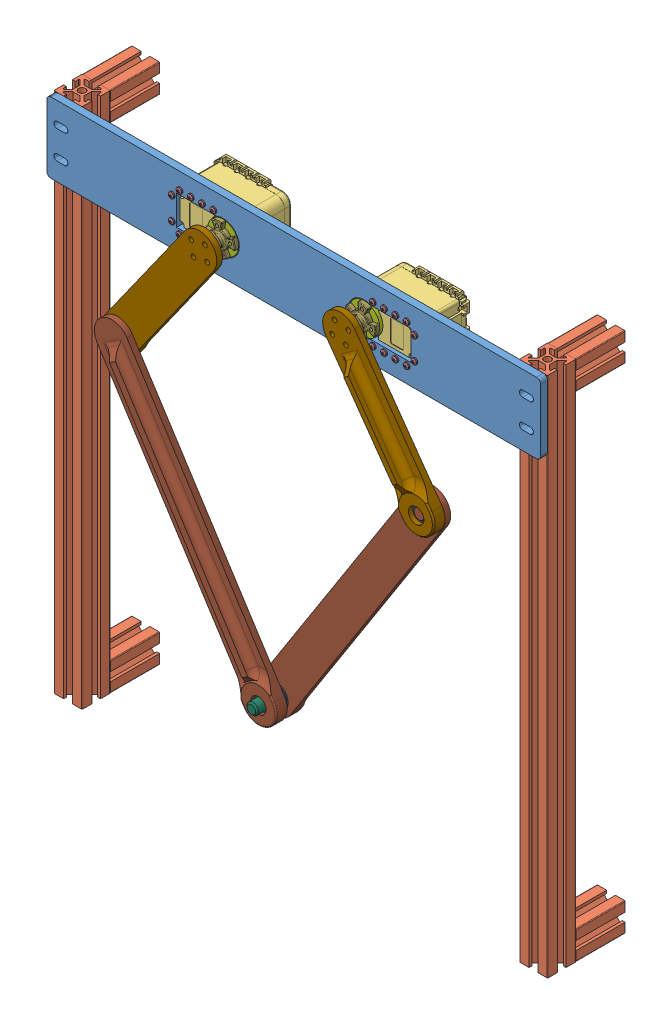
SolidWorks assembly Final Assembly, configuration Default. Lengths in mm.
Overall size (350 370 90).
75 component instances, 15 part files, 116 mates.
Components (placement in the parent):
- Motor Mount Plate-1: Motor Mount Plate [Default] at (0 0 -16) size (350 50 5)
- 2 Dof StrutralBase-1: 2 Dof StrutralBase [Default<As Machined>] at (0 -160 -31) x (1 0 0) z (0 -1 0) size (350 55 370)
- AX-12.stp-1: AX-12.stp [Default] at (-50 0 -37) x (0 -1 0) z (0 0 1) size (32 50 40.86)
  - ASSY_DUMMY__.stp-1: ASSY_DUMMY__.stp [Default] at origin size (32 50 38)
  - ASSY_GEAR-WHEEL__.stp-1: ASSY_GEAR-WHEEL__.stp [Default] at (0 0 -1.8) size (6.5 6.5 5.5)
  - DX124_SCREW-COVER__.stp-1: DX124_SCREW-COVER__.stp [Default] at (9 8.5 14.6) x (-1 0 0) z (0 1 0) size (3.5 30.65 3.5)
  - DX124_SCREW-COVER__.stp-2: DX124_SCREW-COVER__.stp [Default] at (-9 8.5 14.6) x (-1 0 0) z (0 1 0) size (3.5 30.65 3.5)
  - DX124_SCREW-COVER__.stp-3: DX124_SCREW-COVER__.stp [Default] at (9.15 -31.65 14.6) x (-1 0 0) z (0 1 0) size (3.5 30.65 3.5)
  - DX124_SCREW-COVER__.stp-4: DX124_SCREW-COVER__.stp [Default] at (-9 -31.65 14.6) x (-1 0 0) z (0 1 0) size (3.5 30.65 3.5)
  - 099990987___.stp-1: 099990987___.stp [Default] at (5.35 -15.67 -8.55) x (1 0 0) z (0 1 0) size (9.9 9.4 4.9)
  - 099990987___.stp-2: 099990987___.stp [Default] at (-5.3 -15.67 -8.55) x (1 0 0) z (0 1 0) size (9.9 9.4 4.9)
  - DX124_HORN1__.stp-1: DX124_HORN1__.stp [Default] at (0 0 19) x (0 1 0) z (0 0 1) size (22 22 7.6)
  - PHS_M3X10__.stp-1: PHS_M3X10__.stp [Default] at (0 0 19.9) x (-1 0 0) z (0 1 0) size (5.5 11.96 5.5)
- AX-12.stp-2: AX-12.stp [Default] at (50 0 -37) x (0 1 0) z (0 0 1) size (32 50 40.86)
  - ASSY_DUMMY__.stp-1: ASSY_DUMMY__.stp [Default] at origin size (32 50 38)
  - ASSY_GEAR-WHEEL__.stp-1: ASSY_GEAR-WHEEL__.stp [Default] at (0 0 -1.8) size (6.5 6.5 5.5)
  - DX124_SCREW-COVER__.stp-1: DX124_SCREW-COVER__.stp [Default] at (9 8.5 14.6) x (-1 0 0) z (0 1 0) size (3.5 30.65 3.5)
  - DX124_SCREW-COVER__.stp-2: DX124_SCREW-COVER__.stp [Default] at (-9 8.5 14.6) x (-1 0 0) z (0 1 0) size (3.5 30.65 3.5)
  - DX124_SCREW-COVER__.stp-3: DX124_SCREW-COVER__.stp [Default] at (9.15 -31.65 14.6) x (-1 0 0) z (0 1 0) size (3.5 30.65 3.5)
  - DX124_SCREW-COVER__.stp-4: DX124_SCREW-COVER__.stp [Default] at (-9 -31.65 14.6) x (-1 0 0) z (0 1 0) size (3.5 30.65 3.5)
  - 099990987___.stp-1: 099990987___.stp [Default] at (5.35 -15.67 -8.55) x (1 0 0) z (0 1 0) size (9.9 9.4 4.9)
  - 099990987___.stp-2: 099990987___.stp [Default] at (-5.3 -15.67 -8.55) x (1 0 0) z (0 1 0) size (9.9 9.4 4.9)
  - DX124_HORN1__.stp-1: DX124_HORN1__.stp [Default] at (0 0 19) x (0 1 0) z (0 0 1) size (22 22 7.6)
  - PHS_M3X10__.stp-1: PHS_M3X10__.stp [Default] at (0 0 19.9) x (-1 0 0) z (0 1 0) size (5.5 11.96 5.5)
- Top Link-5: Top Link [Default] at (0 0 -3) size (82.85 106.57 12)
- Top Link-6: Top Link [Default] at (0 0 1) x (-1 0 0) z (0 0 -1) size (82.85 106.57 12)
- Ball Bearing 8 x 16 x 5.step-1: Ball Bearing 8 x 16 x 5.step [Default] at (-107.8481 -81.5696 -1.5) x (0 0 -1) z (-0.985237 -0.171198 0) size (5 16 16)
- Ball Bearing 8 x 16 x 5.step-2: Ball Bearing 8 x 16 x 5.step [Default] at (107.8481 -81.5696 -0.5) x (0 0 -1) z (0.941995 -0.335626 0) size (5 16 16)
- Bottom Link-4: Bottom Link [Default] at (-107.8481 -81.5696 1) x (0.842152 0.53924 0) z (0 0 1) size (25 225 16.9)
- Bottom Link-5: Bottom Link [Default] at (107.8481 -81.5696 -3) x (-0.842152 0.53924 0) z (0 0 -1) size (25 225 16.9)
- Ball Bearing 8 x 16 x 5.step-3: Ball Bearing 8 x 16 x 5.step [Default] at (0 -250 -5.5) x (0 0 -1) z (-0.399255 -0.91684 0) size (5 16 16)
- Ball Bearing 8 x 16 x 5.step-4: Ball Bearing 8 x 16 x 5.step [Default] at (0 -250 3.5) x (0 0 -1) z (-0.399255 -0.91684 0) size (5 16 16)
- Horn Mount-3: Horn Mount [Default] at (-50 0 -16) x (0.985832 0.167737 0) z (0 0 1) size (22 22 13)
- Horn Mount-4: Horn Mount [Default] at (50 0 -16) x (0.985832 -0.167737 0) z (0 0 1) size (22 22 13)
- pan head cross recess screw_iso-1: pan head cross recess screw_iso [ISO 7045 - M2 x 10 - Z - 10N] at (-72.5 13.5 -14.4) x (0 0 -1) z (1 0 0) size (11.57 4 4)
- pan head cross recess screw_iso-2: pan head cross recess screw_iso [ISO 7045 - M2 x 10 - Z - 10N] at (-80.5 13.5 -14.4) x (0 0 -1) z (1 0 0) size (11.57 4 4)
- pan head cross recess screw_iso-3: pan head cross recess screw_iso [ISO 7045 - M2 x 10 - Z - 10N] at (-86 8 -14.4) x (0 0 -1) z (1 0 0) size (11.57 4 4)
- pan head cross recess screw_iso-4: pan head cross recess screw_iso [ISO 7045 - M2 x 10 - Z - 10N] at (-86 -8 -14.4) x (0 0 -1) z (1 0 0) size (11.57 4 4)
- pan head cross recess screw_iso-5: pan head cross recess screw_iso [ISO 7045 - M2 x 10 - Z - 10N] at (-80.5 -13.5 -14.4) x (0 0 -1) z (1 0 0) size (11.57 4 4)
- pan head cross recess screw_iso-6: pan head cross recess screw_iso [ISO 7045 - M2 x 10 - Z - 10N] at (-72.5 -13.5 -14.4) x (0 0 -1) z (1 0 0) size (11.57 4 4)
- pan head cross recess screw_iso-7: pan head cross recess screw_iso [ISO 7045 - M2 x 10 - Z - 10N] at (-64.5 -13.5 -14.4) x (0 0 -1) z (1 0 0) size (11.57 4 4)
- pan head cross recess screw_iso-8: pan head cross recess screw_iso [ISO 7045 - M2 x 10 - Z - 10N] at (-56.5 -13.5 -14.4) x (0 0 -1) z (1 0 0) size (11.57 4 4)
- pan head cross recess screw_iso-9: pan head cross recess screw_iso [ISO 7045 - M2 x 10 - Z - 10N] at (-64.5 13.5 -14.4) x (0 0 -1) z (1 0 0) size (11.57 4 4)
- pan head cross recess screw_iso-10: pan head cross recess screw_iso [ISO 7045 - M2 x 10 - Z - 10N] at (-56.5 13.5 -14.4) x (0 0 -1) z (1 0 0) size (11.57 4 4)
- pan head cross recess screw_iso-11: pan head cross recess screw_iso [ISO 7045 - M2 x 10 - Z - 10N] at (56.5 13.5 -14.4) x (0 0 -1) z (1 0 0) size (11.57 4 4)
- pan head cross recess screw_iso-12: pan head cross recess screw_iso [ISO 7045 - M2 x 10 - Z - 10N] at (64.5 13.5 -14.4) x (0 0 -1) z (1 0 0) size (11.57 4 4)
- pan head cross recess screw_iso-13: pan head cross recess screw_iso [ISO 7045 - M2 x 10 - Z - 10N] at (72.5 13.5 -14.4) x (0 0 -1) z (1 0 0) size (11.57 4 4)
- pan head cross recess screw_iso-14: pan head cross recess screw_iso [ISO 7045 - M2 x 10 - Z - 10N] at (80.5 13.5 -14.4) x (0 0 -1) z (1 0 0) size (11.57 4 4)
- pan head cross recess screw_iso-15: pan head cross recess screw_iso [ISO 7045 - M2 x 10 - Z - 10N] at (86 8 -14.4) x (0 0 -1) z (1 0 0) size (11.57 4 4)
- pan head cross recess screw_iso-16: pan head cross recess screw_iso [ISO 7045 - M2 x 10 - Z - 10N] at (86 -8 -14.4) x (0 0 -1) z (1 0 0) size (11.57 4 4)
- pan head cross recess screw_iso-17: pan head cross recess screw_iso [ISO 7045 - M2 x 10 - Z - 10N] at (80.5 -13.5 -14.4) x (0 0 -1) z (1 0 0) size (11.57 4 4)
- pan head cross recess screw_iso-18: pan head cross recess screw_iso [ISO 7045 - M2 x 10 - Z - 10N] at (72.5 -13.5 -14.4) x (0 0 -1) z (1 0 0) size (11.57 4 4)
- pan head cross recess screw_iso-19: pan head cross recess screw_iso [ISO 7045 - M2 x 10 - Z - 10N] at (64.5 -13.5 -14.4) x (0 0 -1) z (1 0 0) size (11.57 4 4)
- pan head cross recess screw_iso-20: pan head cross recess screw_iso [ISO 7045 - M2 x 10 - Z - 10N] at (56.5 -13.5 -14.4) x (0 0 -1) z (1 0 0) size (11.57 4 4)
- hex nut style 1 gradeab_iso-1: hex nut style 1 gradeab_iso [ISO - 4032 - M2 - W - N] at (56.5 13.5 -25.1) x (0.923728 0.383049 0) z (0 0 -1) size (4 4.62 1.6)
- hex nut style 1 gradeab_iso-2: hex nut style 1 gradeab_iso [ISO - 4032 - M2 - W - N] at (64.5 13.5 -25.1) x (0.923728 0.383049 0) z (0 0 -1) size (4 4.62 1.6)
- hex nut style 1 gradeab_iso-3: hex nut style 1 gradeab_iso [ISO - 4032 - M2 - W - N] at (72.5 13.5 -25.1) x (0.923728 0.383049 0) z (0 0 -1) size (4 4.62 1.6)
- hex nut style 1 gradeab_iso-4: hex nut style 1 gradeab_iso [ISO - 4032 - M2 - W - N] at (80.5 13.5 -25.1) x (0.923728 0.383049 0) z (0 0 -1) size (4 4.62 1.6)
- hex nut style 1 gradeab_iso-5: hex nut style 1 gradeab_iso [ISO - 4032 - M2 - W - N] at (86 8 -25.1) x (0.923728 0.383049 0) z (0 0 -1) size (4 4.62 1.6)
- hex nut style 1 gradeab_iso-6: hex nut style 1 gradeab_iso [ISO - 4032 - M2 - W - N] at (86 -8 -25.1) x (0.923728 0.383049 0) z (0 0 -1) size (4 4.62 1.6)
- hex nut style 1 gradeab_iso-7: hex nut style 1 gradeab_iso [ISO - 4032 - M2 - W - N] at (80.5 -13.5 -25.1) x (0.923728 0.383049 0) z (0 0 -1) size (4 4.62 1.6)
- hex nut style 1 gradeab_iso-8: hex nut style 1 gradeab_iso [ISO - 4032 - M2 - W - N] at (72.5 -13.5 -25.1) x (0.923728 0.383049 0) z (0 0 -1) size (4 4.62 1.6)
- hex nut style 1 gradeab_iso-9: hex nut style 1 gradeab_iso [ISO - 4032 - M2 - W - N] at (64.5 -13.5 -25.1) x (0.923728 0.383049 0) z (0 0 -1) size (4 4.62 1.6)
- hex nut style 1 gradeab_iso-10: hex nut style 1 gradeab_iso [ISO - 4032 - M2 - W - N] at (56.5 -13.5 -25.1) x (0.923728 0.383049 0) z (0 0 -1) size (4 4.62 1.6)
- hex nut style 1 gradeab_iso-11: hex nut style 1 gradeab_iso [ISO - 4032 - M2 - W - N] at (-56.5 -13.5 -25.1) x (0.923728 0.383049 0) z (0 0 -1) size (4 4.62 1.6)
- hex nut style 1 gradeab_iso-12: hex nut style 1 gradeab_iso [ISO - 4032 - M2 - W - N] at (-64.5 -13.5 -25.1) x (0.923728 0.383049 0) z (0 0 -1) size (4 4.62 1.6)
- hex nut style 1 gradeab_iso-13: hex nut style 1 gradeab_iso [ISO - 4032 - M2 - W - N] at (-72.5 -13.5 -25.1) x (0.923728 0.383049 0) z (0 0 -1) size (4 4.62 1.6)
- hex nut style 1 gradeab_iso-14: hex nut style 1 gradeab_iso [ISO - 4032 - M2 - W - N] at (-80.5 -13.5 -25.1) x (0.923728 0.383049 0) z (0 0 -1) size (4 4.62 1.6)
- hex nut style 1 gradeab_iso-15: hex nut style 1 gradeab_iso [ISO - 4032 - M2 - W - N] at (-86 -8 -25.1) x (0.923728 0.383049 0) z (0 0 -1) size (4 4.62 1.6)
- hex nut style 1 gradeab_iso-16: hex nut style 1 gradeab_iso [ISO - 4032 - M2 - W - N] at (-86 8 -25.1) x (0.923728 0.383049 0) z (0 0 -1) size (4 4.62 1.6)
- hex nut style 1 gradeab_iso-17: hex nut style 1 gradeab_iso [ISO - 4032 - M2 - W - N] at (-80.5 13.5 -25.1) x (0.923728 0.383049 0) z (0 0 -1) size (4 4.62 1.6)
- hex nut style 1 gradeab_iso-18: hex nut style 1 gradeab_iso [ISO - 4032 - M2 - W - N] at (-72.5 13.5 -25.1) x (0.923728 0.383049 0) z (0 0 -1) size (4 4.62 1.6)
- hex nut style 1 gradeab_iso-19: hex nut style 1 gradeab_iso [ISO - 4032 - M2 - W - N] at (-64.5 13.5 -25.1) x (0.923728 0.383049 0) z (0 0 -1) size (4 4.62 1.6)
- hex nut style 1 gradeab_iso-20: hex nut style 1 gradeab_iso [ISO - 4032 - M2 - W - N] at (-56.5 13.5 -25.1) x (0.923728 0.383049 0) z (0 0 -1) size (4 4.62 1.6)
- Temp Pin 8.0-1: Temp Pin 8.0 [Default] at (0 -250 -1) x (1 0 0) z (0 -1 0) size (8 30 8)
Mates (geometry in assembly coordinates):
- Mechanism Lock: concentric: cylinder of Bottom Link-4 through (0 -250 5) axis (0 0 -1) radius 12.5
- Concentric5: concentric aligned: circle of Motor Mount Plate-1; cone of AX-12.stp-1/DX124_HORN1__.stp-1 through (-50 0 -18) axis (0 0 1)
- Parallel1: parallel aligned: plane of Motor Mount Plate-1 through (-175 25 -21) normal (0 1 0); plane of AX-12.stp-1/ASSY_DUMMY__.stp-1 through (-38.5 13 -56) normal (0 1 0)
- Concentric6: concentric aligned: circle of Motor Mount Plate-1; circle of AX-12.stp-2/DX124_HORN1__.stp-1
- Parallel2: parallel aligned: plane of Motor Mount Plate-1 through (-175 25 -21) normal (0 1 0); plane of AX-12.stp-2/ASSY_DUMMY__.stp-1 through (85.5 13 -56) normal (0 1 0)
- Coincident11: coincident anti-aligned: plane of Motor Mount Plate-1 through (0 0 -21) normal (0 0 -1); plane of AX-12.stp-2/ASSY_DUMMY__.stp-1 through (50 0 -21) normal (0 0 1)
- Coincident12: coincident anti-aligned: plane of Motor Mount Plate-1 through (0 0 -21) normal (0 0 -1); plane of AX-12.stp-1/ASSY_DUMMY__.stp-1 through (-50 0 -21) normal (0 0 1)
- Parallel3: parallel: plane of Motor Mount Plate-1 through (-175 25 -21) normal (0 1 0)
- Concentric25: concentric anti-aligned: cylinder of Top Link-5 through (-107.8481 -81.5696 -4) axis (0 0 1) radius 8.05; cylinder of Ball Bearing 8 x 16 x 5.step-1 through (-107.8481 -81.5696 -1.5) axis (0 0 -1) radius 8
- Coincident18: coincident anti-aligned: plane of Top Link-5 through (-107.8481 -81.5696 -4) normal (0 0 1); plane of Ball Bearing 8 x 16 x 5.step-1 through (-106.6154 -88.6633 -4) normal (0 0 -1)
- Concentric26: concentric aligned: cylinder of Top Link-6 through (107.8481 -81.5696 2) axis (0 0 -1) radius 8.05; cylinder of Ball Bearing 8 x 16 x 5.step-2 through (107.8481 -81.5696 -0.5) axis (0 0 -1) radius 4
- Coincident19: coincident anti-aligned: plane of Top Link-6 through (107.8481 -81.5696 2) normal (0 0 -1); plane of Ball Bearing 8 x 16 x 5.step-2 through (110.2646 -74.7872 2) normal (0 0 1)
- Concentric27: concentric aligned: cylinder of Top Link-5 through (-107.8481 -81.5696 1) axis (0 0 -1) radius 12.5; cylinder of Bottom Link-4 through (-107.8481 -81.5696 5) axis (0 0 -1) radius 12.5
- Coincident20: coincident anti-aligned: plane of Top Link-5 through (0 0 1) normal (0 0 1); plane of Bottom Link-4 through (-107.8481 -81.5696 1) normal (0 0 -1)
- Concentric28: concentric aligned: cylinder of Ball Bearing 8 x 16 x 5.step-2 through (107.8481 -81.5696 -0.5) axis (0 0 -1) radius 4; cylinder of Bottom Link-5 through (107.8481 -81.5696 3) axis (0 0 -1) radius 4.05
- Coincident21: coincident anti-aligned: plane of Ball Bearing 8 x 16 x 5.step-2 through (110.2646 -74.7872 -3) normal (0 0 -1); plane of Bottom Link-5 through (107.8481 -81.5696 -3) normal (0 0 1)
- Concentric29: concentric anti-aligned: cylinder of Bottom Link-4 through (0 -250 5) axis (0 0 -1) radius 12.5; cylinder of Bottom Link-5 through (0 -250 -7) axis (0 0 1) radius 12.5
- Concentric30: concentric anti-aligned: cylinder of Bottom Link-5 through (0 -250 -8) axis (0 0 1) radius 8.05; cylinder of Ball Bearing 8 x 16 x 5.step-3 through (0 -250 -5.5) axis (0 0 -1) radius 8
- Coincident22: coincident anti-aligned: plane of Bottom Link-5 through (0 -250 -8) normal (0 0 1); plane of Ball Bearing 8 x 16 x 5.step-3 through (6.6012 -252.8746 -8) normal (0 0 -1)
- Concentric31: concentric aligned: cylinder of Bottom Link-4 through (0 -250 6) axis (0 0 -1) radius 8.05; cylinder of Ball Bearing 8 x 16 x 5.step-4 through (0 -250 3.5) axis (0 0 -1) radius 8
- Coincident23: coincident anti-aligned: plane of Bottom Link-4 through (0 -250 6) normal (0 0 -1); plane of Ball Bearing 8 x 16 x 5.step-4 through (6.6012 -252.8746 6) normal (0 0 1)
- Concentric40: concentric anti-aligned: cone of AX-12.stp-1/DX124_HORN1__.stp-1 through (-50 0 -18) axis (0 0 1); cylinder of Horn Mount-3 through (-50 0 -13) axis (0 0 -1) radius 11
- Coincident30: coincident anti-aligned: plane of AX-12.stp-1/DX124_HORN1__.stp-1 through (-50 0 -16) normal (0 0 1); plane of Horn Mount-3 through (-50 0 -16) normal (0 0 -1)
- Concentric42: concentric anti-aligned: cone of AX-12.stp-2/DX124_HORN1__.stp-1 through (50 0 -18) axis (0 0 1); cylinder of Horn Mount-4 through (50 0 -13) axis (0 0 -1) radius 11
- Coincident31: coincident anti-aligned: plane of AX-12.stp-2/DX124_HORN1__.stp-1 through (50 0 -16) normal (0 0 1); plane of Horn Mount-4 through (50 0 -16) normal (0 0 -1)
- Concentric43: concentric aligned: cylinder of Top Link-5 through (-55.7099 4.0494 -7.001) axis (0 0 1) radius 1.65; cylinder of Horn Mount-3 through (-55.7099 4.0494 -16.001) axis (0 0 1) radius 1.65
- Concentric44: concentric aligned: cylinder of Top Link-5 through (-45.9506 5.7099 -7.001) axis (0 0 1) radius 1.65; cylinder of Horn Mount-3 through (-45.9506 5.7099 -16.001) axis (0 0 1) radius 1.65
- Coincident32: coincident anti-aligned: plane of Top Link-5 through (0 0 -3) normal (0 0 -1); plane of Horn Mount-3 through (-50 0 -3) normal (0 0 1)
- Concentric45: concentric anti-aligned: cylinder of Top Link-6 through (45.9506 5.7099 5.001) axis (0 0 -1) radius 1.65; cylinder of Horn Mount-4 through (45.9506 5.7099 -16.001) axis (0 0 1) radius 1.65
- Coincident33: coincident anti-aligned: plane of Top Link-6 through (0 0 -3) normal (0 0 -1); plane of Horn Mount-4 through (50 0 -3) normal (0 0 1)
- Concentric46: concentric anti-aligned: cylinder of Top Link-6 through (55.7099 4.0494 5.001) axis (0 0 -1) radius 1.65; cylinder of Horn Mount-4 through (55.7099 4.0494 -16.001) axis (0 0 1) radius 1.65
- Concentric47: concentric aligned: cylinder of Motor Mount Plate-1 through (-72.5 13.5 -21.001) axis (0 0 1) radius 1.15; cylinder of pan head cross recess screw_iso-1 through (-72.5 13.5 11) axis (0 0 1) radius 2
- Coincident34: coincident anti-aligned: plane of Motor Mount Plate-1 through (0 0 -16) normal (0 0 1); plane of pan head cross recess screw_iso-1 through (-72.5 14.5 -16) normal (0 0 -1)
- Concentric48: concentric aligned: cylinder of Motor Mount Plate-1 through (-80.5 13.5 -21.001) axis (0 0 1) radius 1.15; cylinder of pan head cross recess screw_iso-2 through (-80.5 13.5 11) axis (0 0 1) radius 2
- Coincident35: coincident anti-aligned: plane of Motor Mount Plate-1 through (0 0 -16) normal (0 0 1); plane of pan head cross recess screw_iso-2 through (-80.5 14.5 -16) normal (0 0 -1)
- Concentric49: concentric aligned: cylinder of Motor Mount Plate-1 through (-86 8 -21.001) axis (0 0 1) radius 1.15; cylinder of pan head cross recess screw_iso-3 through (-86 8 11) axis (0 0 1) radius 2
- Coincident36: coincident anti-aligned: plane of Motor Mount Plate-1 through (0 0 -16) normal (0 0 1); plane of pan head cross recess screw_iso-3 through (-86 9 -16) normal (0 0 -1)
- Concentric50: concentric aligned: cylinder of Motor Mount Plate-1 through (-86 -8 -21.001) axis (0 0 1) radius 1.15; cylinder of pan head cross recess screw_iso-4 through (-86 -8 11) axis (0 0 1) radius 2
- Coincident37: coincident anti-aligned: plane of Motor Mount Plate-1 through (0 0 -16) normal (0 0 1); plane of pan head cross recess screw_iso-4 through (-86 -7 -16) normal (0 0 -1)
- Concentric51: concentric aligned: cylinder of Motor Mount Plate-1 through (-80.5 -13.5 -21.001) axis (0 0 1) radius 1.15; cylinder of pan head cross recess screw_iso-5 through (-80.5 -13.5 11) axis (0 0 1) radius 2
- Coincident38: coincident anti-aligned: plane of Motor Mount Plate-1 through (0 0 -16) normal (0 0 1); plane of pan head cross recess screw_iso-5 through (-80.5 -12.5 -16) normal (0 0 -1)
- Concentric52: concentric aligned: cylinder of Motor Mount Plate-1 through (-72.5 -13.5 -21.001) axis (0 0 1) radius 1.15; cylinder of pan head cross recess screw_iso-6 through (-72.5 -13.5 11) axis (0 0 1) radius 2
- Coincident39: coincident anti-aligned: plane of Motor Mount Plate-1 through (0 0 -16) normal (0 0 1); plane of pan head cross recess screw_iso-6 through (-72.5 -12.5 -16) normal (0 0 -1)
- Concentric53: concentric aligned: cylinder of Motor Mount Plate-1 through (-64.5 -13.5 -21.001) axis (0 0 1) radius 1.15; cylinder of pan head cross recess screw_iso-7 through (-64.5 -13.5 11) axis (0 0 1) radius 2
- Coincident40: coincident anti-aligned: plane of Motor Mount Plate-1 through (0 0 -16) normal (0 0 1); plane of pan head cross recess screw_iso-7 through (-64.5 -12.5 -16) normal (0 0 -1)
- Concentric54: concentric aligned: cylinder of Motor Mount Plate-1 through (-56.5 -13.5 -21.001) axis (0 0 1) radius 1.15; cylinder of pan head cross recess screw_iso-8 through (-56.5 -13.5 11) axis (0 0 1) radius 2
- Coincident41: coincident anti-aligned: plane of Motor Mount Plate-1 through (0 0 -16) normal (0 0 1); plane of pan head cross recess screw_iso-8 through (-56.5 -12.5 -16) normal (0 0 -1)
- Concentric551: concentric aligned: cylinder of Motor Mount Plate-1 through (-64.5 13.5 -21.001) axis (0 0 1) radius 1.15; cylinder of pan head cross recess screw_iso-9 through (-64.5 13.5 11) axis (0 0 1) radius 2
- Coincident421: coincident anti-aligned: plane of Motor Mount Plate-1 through (0 0 -16) normal (0 0 1); plane of pan head cross recess screw_iso-9 through (-64.5 14.5 -16) normal (0 0 -1)
- Concentric56: concentric aligned: cylinder of Motor Mount Plate-1 through (-56.5 13.5 -21.001) axis (0 0 1) radius 1.15; cylinder of pan head cross recess screw_iso-10 through (-56.5 13.5 11) axis (0 0 1) radius 2
- Coincident43: coincident anti-aligned: plane of Motor Mount Plate-1 through (0 0 -16) normal (0 0 1); plane of pan head cross recess screw_iso-10 through (-56.5 14.5 -16) normal (0 0 -1)
- Concentric57: concentric aligned: cylinder of Motor Mount Plate-1 through (56.5 13.5 -21.001) axis (0 0 1) radius 1.15; cylinder of pan head cross recess screw_iso-11 through (56.5 13.5 11) axis (0 0 1) radius 2
- Coincident44: coincident anti-aligned: plane of Motor Mount Plate-1 through (0 0 -16) normal (0 0 1); plane of pan head cross recess screw_iso-11 through (56.5 14.5 -16) normal (0 0 -1)
- Concentric58: concentric aligned: cylinder of Motor Mount Plate-1 through (64.5 13.5 -21.001) axis (0 0 1) radius 1.15; cylinder of pan head cross recess screw_iso-12 through (64.5 13.5 11) axis (0 0 1) radius 2
- Coincident45: coincident anti-aligned: plane of Motor Mount Plate-1 through (0 0 -16) normal (0 0 1); plane of pan head cross recess screw_iso-12 through (64.5 14.5 -16) normal (0 0 -1)
- Concentric59: concentric aligned: cylinder of Motor Mount Plate-1 through (72.5 13.5 -21.001) axis (0 0 1) radius 1.15; cylinder of pan head cross recess screw_iso-13 through (72.5 13.5 11) axis (0 0 1) radius 2
- Coincident46: coincident anti-aligned: plane of Motor Mount Plate-1 through (0 0 -16) normal (0 0 1); plane of pan head cross recess screw_iso-13 through (72.5 14.5 -16) normal (0 0 -1)
- Concentric60: concentric aligned: cylinder of Motor Mount Plate-1 through (80.5 13.5 -21.001) axis (0 0 1) radius 1.15; cylinder of pan head cross recess screw_iso-14 through (80.5 13.5 11) axis (0 0 1) radius 2
- Coincident47: coincident anti-aligned: plane of Motor Mount Plate-1 through (0 0 -16) normal (0 0 1); plane of pan head cross recess screw_iso-14 through (80.5 14.5 -16) normal (0 0 -1)
- Concentric61: concentric aligned: cylinder of Motor Mount Plate-1 through (86 8 -21.001) axis (0 0 1) radius 1.15; cylinder of pan head cross recess screw_iso-15 through (86 8 11) axis (0 0 1) radius 2
- Coincident48: coincident anti-aligned: plane of Motor Mount Plate-1 through (0 0 -16) normal (0 0 1); plane of pan head cross recess screw_iso-15 through (86 9 -16) normal (0 0 -1)
- Concentric62: concentric aligned: cylinder of Motor Mount Plate-1 through (86 -8 -21.001) axis (0 0 1) radius 1.15; cylinder of pan head cross recess screw_iso-16 through (86 -8 11) axis (0 0 1) radius 2
- Coincident49: coincident anti-aligned: plane of Motor Mount Plate-1 through (0 0 -16) normal (0 0 1); plane of pan head cross recess screw_iso-16 through (86 -7 -16) normal (0 0 -1)
- Concentric63: concentric aligned: cylinder of Motor Mount Plate-1 through (80.5 -13.5 -21.001) axis (0 0 1) radius 1.15; cylinder of pan head cross recess screw_iso-17 through (80.5 -13.5 11) axis (0 0 1) radius 2
- Coincident50: coincident anti-aligned: plane of Motor Mount Plate-1 through (0 0 -16) normal (0 0 1); plane of pan head cross recess screw_iso-17 through (80.5 -12.5 -16) normal (0 0 -1)
- Concentric64: concentric aligned: cylinder of Motor Mount Plate-1 through (72.5 -13.5 -21.001) axis (0 0 1) radius 1.15; cylinder of pan head cross recess screw_iso-18 through (72.5 -13.5 11) axis (0 0 1) radius 2
- Coincident51: coincident anti-aligned: plane of Motor Mount Plate-1 through (0 0 -16) normal (0 0 1); plane of pan head cross recess screw_iso-18 through (72.5 -12.5 -16) normal (0 0 -1)
- Concentric65: concentric aligned: cylinder of Motor Mount Plate-1 through (64.5 -13.5 -21.001) axis (0 0 1) radius 1.15; cylinder of pan head cross recess screw_iso-19 through (64.5 -13.5 11) axis (0 0 1) radius 2
- Coincident52: coincident anti-aligned: plane of Motor Mount Plate-1 through (0 0 -16) normal (0 0 1); plane of pan head cross recess screw_iso-19 through (64.5 -12.5 -16) normal (0 0 -1)
- Concentric66: concentric aligned: cylinder of Motor Mount Plate-1 through (56.5 -13.5 -21.001) axis (0 0 1) radius 1.15; cylinder of pan head cross recess screw_iso-20 through (56.5 -13.5 11) axis (0 0 1) radius 2
- Coincident53: coincident anti-aligned: plane of Motor Mount Plate-1 through (0 0 -16) normal (0 0 1); plane of pan head cross recess screw_iso-20 through (56.5 -12.5 -16) normal (0 0 -1)
- Concentric67: concentric anti-aligned: cylinder of AX-12.stp-2/ASSY_DUMMY__.stp-1 through (56.5 13.5 -21) axis (0 0 1) radius 1.1; cylinder of hex nut style 1 gradeab_iso-1 through (56.5 13.5 -0.0625) axis (0 0 -1) radius 1
- Coincident54: coincident anti-aligned: plane of AX-12.stp-2/ASSY_DUMMY__.stp-1 through (50 0 -23.5) normal (0 0 -1); plane of hex nut style 1 gradeab_iso-1 through (57.3846 11.3667 -23.5) normal (0 0 1)
- Concentric68: concentric anti-aligned: cylinder of AX-12.stp-2/ASSY_DUMMY__.stp-1 through (64.5 13.5 -21) axis (0 0 1) radius 1.1; cylinder of hex nut style 1 gradeab_iso-2 through (64.5 13.5 -0.0625) axis (0 0 -1) radius 1
- Coincident55: coincident anti-aligned: plane of AX-12.stp-2/ASSY_DUMMY__.stp-1 through (50 0 -23.5) normal (0 0 -1); plane of hex nut style 1 gradeab_iso-2 through (65.3846 11.3667 -23.5) normal (0 0 1)
- Concentric69: concentric anti-aligned: cylinder of AX-12.stp-2/ASSY_DUMMY__.stp-1 through (72.5 13.5 -21) axis (0 0 1) radius 1.1; cylinder of hex nut style 1 gradeab_iso-3 through (72.5 13.5 -0.0625) axis (0 0 -1) radius 1
- Coincident56: coincident anti-aligned: plane of AX-12.stp-2/ASSY_DUMMY__.stp-1 through (50 0 -23.5) normal (0 0 -1); plane of hex nut style 1 gradeab_iso-3 through (73.3846 11.3667 -23.5) normal (0 0 1)
- Concentric70: concentric anti-aligned: cylinder of AX-12.stp-2/ASSY_DUMMY__.stp-1 through (80.5 13.5 -21) axis (0 0 1) radius 1.1; cylinder of hex nut style 1 gradeab_iso-4 through (80.5 13.5 -0.0625) axis (0 0 -1) radius 1
- Coincident57: coincident anti-aligned: plane of AX-12.stp-2/ASSY_DUMMY__.stp-1 through (50 0 -23.5) normal (0 0 -1); plane of hex nut style 1 gradeab_iso-4 through (81.3846 11.3667 -23.5) normal (0 0 1)
- Concentric71: concentric anti-aligned: cylinder of AX-12.stp-2/ASSY_DUMMY__.stp-1 through (86 8 -21) axis (0 0 1) radius 1.1; cylinder of hex nut style 1 gradeab_iso-5 through (86 8 -0.0625) axis (0 0 -1) radius 1
- Coincident58: coincident anti-aligned: plane of AX-12.stp-2/ASSY_DUMMY__.stp-1 through (50 0 -23.5) normal (0 0 -1); plane of hex nut style 1 gradeab_iso-5 through (86.8846 5.8667 -23.5) normal (0 0 1)
- Concentric72: concentric aligned: cylinder of AX-12.stp-2/ASSY_DUMMY__.stp-1 through (86 -8 -21) axis (0 0 -1) radius 1.1; cylinder of hex nut style 1 gradeab_iso-6 through (86 -8 -0.0625) axis (0 0 -1) radius 1
- Coincident59: coincident anti-aligned: plane of AX-12.stp-2/ASSY_DUMMY__.stp-1 through (50 0 -23.5) normal (0 0 -1); plane of hex nut style 1 gradeab_iso-6 through (86.8846 -10.1333 -23.5) normal (0 0 1)
- Concentric73: concentric aligned: cylinder of AX-12.stp-2/ASSY_DUMMY__.stp-1 through (80.5 -13.5 -21) axis (0 0 -1) radius 1.1; cylinder of hex nut style 1 gradeab_iso-7 through (80.5 -13.5 -0.0625) axis (0 0 -1) radius 1
- Coincident60: coincident anti-aligned: plane of AX-12.stp-2/ASSY_DUMMY__.stp-1 through (50 0 -23.5) normal (0 0 -1); plane of hex nut style 1 gradeab_iso-7 through (81.3846 -15.6333 -23.5) normal (0 0 1)
- Concentric74: concentric aligned: cylinder of AX-12.stp-2/ASSY_DUMMY__.stp-1 through (72.5 -13.5 -21) axis (0 0 -1) radius 1.1; cylinder of hex nut style 1 gradeab_iso-8 through (72.5 -13.5 -0.0625) axis (0 0 -1) radius 1
- Coincident61: coincident anti-aligned: plane of AX-12.stp-2/ASSY_DUMMY__.stp-1 through (50 0 -23.5) normal (0 0 -1); plane of hex nut style 1 gradeab_iso-8 through (73.3846 -15.6333 -23.5) normal (0 0 1)
- Concentric75: concentric aligned: cylinder of AX-12.stp-2/ASSY_DUMMY__.stp-1 through (64.5 -13.5 -21) axis (0 0 -1) radius 1.1; cylinder of hex nut style 1 gradeab_iso-9 through (64.5 -13.5 -0.0625) axis (0 0 -1) radius 1
- Coincident62: coincident anti-aligned: plane of AX-12.stp-2/ASSY_DUMMY__.stp-1 through (50 0 -23.5) normal (0 0 -1); plane of hex nut style 1 gradeab_iso-9 through (65.3846 -15.6333 -23.5) normal (0 0 1)
- Concentric76: concentric aligned: cylinder of AX-12.stp-2/ASSY_DUMMY__.stp-1 through (56.5 -13.5 -21) axis (0 0 -1) radius 1.1; cylinder of hex nut style 1 gradeab_iso-10 through (56.5 -13.5 -0.0625) axis (0 0 -1) radius 1
- Coincident63: coincident anti-aligned: plane of AX-12.stp-2/ASSY_DUMMY__.stp-1 through (50 0 -23.5) normal (0 0 -1); plane of hex nut style 1 gradeab_iso-10 through (57.3846 -15.6333 -23.5) normal (0 0 1)
- Concentric77: concentric anti-aligned: cylinder of AX-12.stp-1/ASSY_DUMMY__.stp-1 through (-56.5 -13.5 -21) axis (0 0 1) radius 1.1; cylinder of hex nut style 1 gradeab_iso-11 through (-56.5 -13.5 -0.0625) axis (0 0 -1) radius 1
- Coincident64: coincident anti-aligned: plane of AX-12.stp-1/ASSY_DUMMY__.stp-1 through (-50 0 -23.5) normal (0 0 -1); plane of hex nut style 1 gradeab_iso-11 through (-55.6154 -15.6333 -23.5) normal (0 0 1)
- Concentric78: concentric anti-aligned: cylinder of AX-12.stp-1/ASSY_DUMMY__.stp-1 through (-64.5 -13.5 -21) axis (0 0 1) radius 1.1; cylinder of hex nut style 1 gradeab_iso-12 through (-64.5 -13.5 -0.0625) axis (0 0 -1) radius 1
- Coincident65: coincident anti-aligned: plane of AX-12.stp-1/ASSY_DUMMY__.stp-1 through (-50 0 -23.5) normal (0 0 -1); plane of hex nut style 1 gradeab_iso-12 through (-63.6154 -15.6333 -23.5) normal (0 0 1)
- Concentric79: concentric anti-aligned: cylinder of AX-12.stp-1/ASSY_DUMMY__.stp-1 through (-72.5 -13.5 -21) axis (0 0 1) radius 1.1; cylinder of hex nut style 1 gradeab_iso-13 through (-72.5 -13.5 -0.0625) axis (0 0 -1) radius 1
- Coincident66: coincident anti-aligned: plane of AX-12.stp-1/ASSY_DUMMY__.stp-1 through (-50 0 -23.5) normal (0 0 -1); plane of hex nut style 1 gradeab_iso-13 through (-71.6154 -15.6333 -23.5) normal (0 0 1)
- Concentric80: concentric anti-aligned: cylinder of AX-12.stp-1/ASSY_DUMMY__.stp-1 through (-80.5 -13.5 -21) axis (0 0 1) radius 1.1; cylinder of hex nut style 1 gradeab_iso-14 through (-80.5 -13.5 -0.0625) axis (0 0 -1) radius 1
- Coincident67: coincident anti-aligned: plane of AX-12.stp-1/ASSY_DUMMY__.stp-1 through (-50 0 -23.5) normal (0 0 -1); plane of hex nut style 1 gradeab_iso-14 through (-79.6154 -15.6333 -23.5) normal (0 0 1)
- Concentric81: concentric anti-aligned: cylinder of AX-12.stp-1/ASSY_DUMMY__.stp-1 through (-86 -8 -21) axis (0 0 1) radius 1.1; cylinder of hex nut style 1 gradeab_iso-15 through (-86 -8 -0.0625) axis (0 0 -1) radius 1
- Coincident68: coincident anti-aligned: plane of AX-12.stp-1/ASSY_DUMMY__.stp-1 through (-50 0 -23.5) normal (0 0 -1); plane of hex nut style 1 gradeab_iso-15 through (-85.1154 -10.1333 -23.5) normal (0 0 1)
- Concentric82: concentric aligned: cylinder of AX-12.stp-1/ASSY_DUMMY__.stp-1 through (-86 8 -21) axis (0 0 -1) radius 1.1; cylinder of hex nut style 1 gradeab_iso-16 through (-86 8 -0.0625) axis (0 0 -1) radius 1
- Coincident69: coincident anti-aligned: plane of AX-12.stp-1/ASSY_DUMMY__.stp-1 through (-50 0 -23.5) normal (0 0 -1); plane of hex nut style 1 gradeab_iso-16 through (-85.1154 5.8667 -23.5) normal (0 0 1)
- Concentric83: concentric aligned: cylinder of AX-12.stp-1/ASSY_DUMMY__.stp-1 through (-80.5 13.5 -21) axis (0 0 -1) radius 1.1; cylinder of hex nut style 1 gradeab_iso-17 through (-80.5 13.5 -0.0625) axis (0 0 -1) radius 1
- Coincident70: coincident anti-aligned: plane of AX-12.stp-1/ASSY_DUMMY__.stp-1 through (-50 0 -23.5) normal (0 0 -1); plane of hex nut style 1 gradeab_iso-17 through (-79.6154 11.3667 -23.5) normal (0 0 1)
- Concentric84: concentric aligned: cylinder of AX-12.stp-1/ASSY_DUMMY__.stp-1 through (-72.5 13.5 -21) axis (0 0 -1) radius 1.1; cylinder of hex nut style 1 gradeab_iso-18 through (-72.5 13.5 -0.0625) axis (0 0 -1) radius 1
- Coincident71: coincident anti-aligned: plane of AX-12.stp-1/ASSY_DUMMY__.stp-1 through (-50 0 -23.5) normal (0 0 -1); plane of hex nut style 1 gradeab_iso-18 through (-71.6154 11.3667 -23.5) normal (0 0 1)
- Concentric85: concentric aligned: cylinder of AX-12.stp-1/ASSY_DUMMY__.stp-1 through (-64.5 13.5 -21) axis (0 0 -1) radius 1.1; cylinder of hex nut style 1 gradeab_iso-19 through (-64.5 13.5 -0.0625) axis (0 0 -1) radius 1
- Coincident72: coincident anti-aligned: plane of AX-12.stp-1/ASSY_DUMMY__.stp-1 through (-50 0 -23.5) normal (0 0 -1); plane of hex nut style 1 gradeab_iso-19 through (-63.6154 11.3667 -23.5) normal (0 0 1)
- Concentric86: concentric aligned: cylinder of AX-12.stp-1/ASSY_DUMMY__.stp-1 through (-56.5 13.5 -21) axis (0 0 -1) radius 1.1; cylinder of hex nut style 1 gradeab_iso-20 through (-56.5 13.5 -0.0625) axis (0 0 -1) radius 1
- Coincident73: coincident anti-aligned: plane of AX-12.stp-1/ASSY_DUMMY__.stp-1 through (-50 0 -23.5) normal (0 0 -1); plane of hex nut style 1 gradeab_iso-20 through (-55.6154 11.3667 -23.5) normal (0 0 1)
- Coincident422: coincident aligned: plane of Motor Mount Plate-1 through (-175 25 -21) normal (0 1 0); plane of 2 Dof StrutralBase-1 through (155 25 -31) normal (0 1 0)
- Coincident423: coincident aligned: plane of Motor Mount Plate-1 through (175 25 -21) normal (1 0 0); plane of 2 Dof StrutralBase-1 through (175 18.1 -76) normal (1 0 0)
- Coincident425: coincident anti-aligned: plane of Motor Mount Plate-1 through (0 0 -21) normal (0 0 -1); plane of 2 Dof StrutralBase-1 through (155.5 -335 -21) normal (0 0 1)
- Concentric552: concentric aligned: cylinder of Ball Bearing 8 x 16 x 5.step-4 through (0 -250 3.5) axis (0 0 -1) radius 4; cylinder of Temp Pin 8.0-1 through (0 -250 14) axis (0 0 -1) radius 4
- Width1: width aligned: plane of Temp Pin 8.0-1 through (0 -250 -16) normal (0 0 -1); plane of Temp Pin 8.0-1 through (0 -250 14) normal (0 0 1); plane of Bottom Link-5 through (0 -250 -11) normal (0 0 -1); plane of Bottom Link-4 through (0 -250 9) normal (0 0 1)
